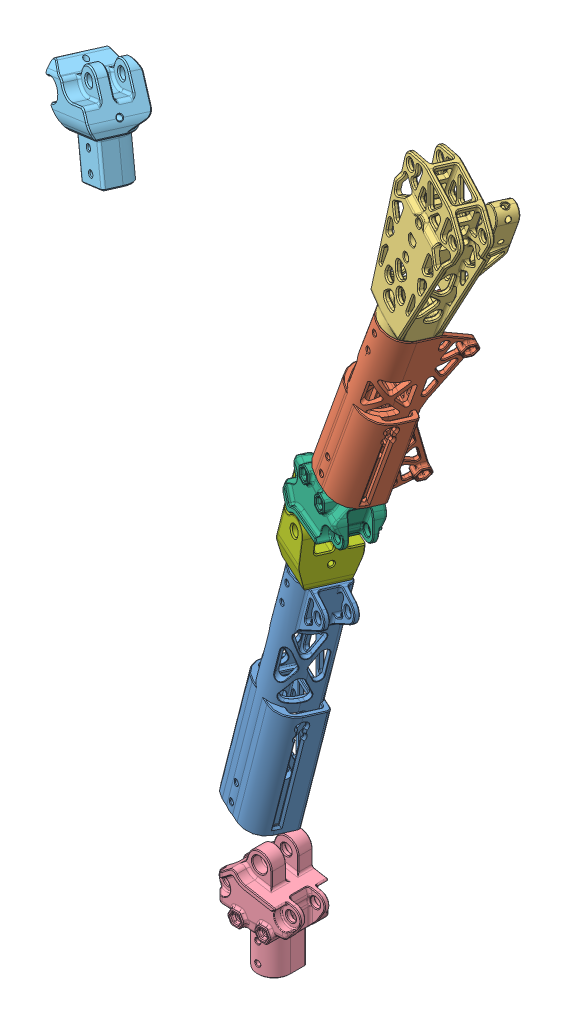
SolidWorks assembly right back leg, configuration Default. Lengths in mm.
Overall size (423.59 516.7 169.39).
7 component instances, 7 part files, 8 mates.
Components (placement in the parent):
- AARL_QR_FR_LE_PL_BL_005.1-4: AARL_QR_FR_LE_PL_BL_005.1 [Default] at (23.665 -332.8832 -154.7317) x (0.294917 -0.089041 -0.951365) z (0.92617 -0.21825 0.307533) size (30.96 157.16 50.8)
- AARL_QR_FR_LE_PL_BL_002.2-4: AARL_QR_FR_LE_PL_BL_002.2 [Default] at (80.0385 -117.9521 -157.1454) x (0.294917 -0.089041 -0.951365) z (0.889564 -0.33792 0.307386) size (49.56 119.06 40.01)
- AARL_QR_FR_LE_PL_BL_012.1-4: AARL_QR_FR_LE_PL_BL_012.1 [Default] at (134.9486 29.5253 -153.9264) x (0.294917 -0.089041 -0.951365) z (0.889564 -0.33792 0.307386) size (53.59 127.48 60.54)
- AARL_QR_FR_LE_PL_BR_003.10-1: AARL_QR_FR_LE_PL_BR_003.10 [Default] at (37.6833 -379.4702 -152.6958) size (54.18 69.85 35.13)
- AARL_QR_FR_LE_PL_BR_004.10-1: AARL_QR_FR_LE_PL_BR_004.10 [Default] at (-195.521 -86.8126 -273.4087) x (0.294917 -0.089041 -0.951365) z (0.906991 0.339364 0.249399) size (36.16 59.22 41.37)
- AARL_QR_FR_LE_PL_BR_006.10-1: AARL_QR_FR_LE_PL_BR_006.10 [Default] at (61.1801 -123.8408 -109.0433) x (0.889564 -0.33792 0.307386) z (0.294917 -0.089041 -0.951365) size (54.18 69.85 35.13)
- AARL_QR_FR_LE_PL_BR_007.10-1: AARL_QR_FR_LE_PL_BR_007.10 [Default] at (67.3646 -152.1819 -158.0975) x (0.294917 -0.089041 -0.951365) z (0.92617 -0.21825 0.307533) size (34.93 68.68 39.69)
Mates (geometry in assembly coordinates):
- Concentric23: concentric aligned: cylinder of AARL_QR_FR_LE_PL_BL_002.2-4 through (121.574 -6.3961 -154.7104) axis (-0.348855 -0.936954 -0.020451) radius 11.1125; cylinder of AARL_QR_FR_LE_PL_BL_012.1-4 through (126.9311 7.992 -154.3964) axis (-0.348855 -0.936954 -0.020451) radius 10.8585
- Concentric24: concentric aligned: cylinder of AARL_QR_FR_LE_PL_BL_002.2-4 through (115.1452 -11.0736 -141.2477) axis (0.294917 -0.089041 -0.951365) radius 1.5875; cylinder of AARL_QR_FR_LE_PL_BL_012.1-4 through (115.6134 -11.2149 -142.758) axis (0.294917 -0.089041 -0.951365) radius 1.5875
- Concentric25: concentric anti-aligned: cylinder of AARL_QR_FR_LE_PL_BL_002.2-4 through (80.0385 -117.9521 -157.1454) axis (0.348855 0.936954 0.020451) radius 11.1125; cylinder of AARL_QR_FR_LE_PL_BR_006.10-1 through (88.8994 -94.1535 -156.6259) axis (-0.348855 -0.936954 -0.020451) radius 10.8585
- Concentric27: concentric aligned: cylinder of AARL_QR_FR_LE_PL_BL_002.2-4 through (82.4705 -98.831 -143.1631) axis (0.294917 -0.089041 -0.951365) radius 1.5875; cylinder of AARL_QR_FR_LE_PL_BR_006.10-1 through (81.5042 -98.5393 -140.0459) axis (0.294917 -0.089041 -0.951365) radius 1.5875
- Concentric30: concentric anti-aligned: cylinder of AARL_QR_FR_LE_PL_BR_006.10-1 through (60.4662 -150.0991 -135.8442) axis (0.294917 -0.089041 -0.951365) radius 4.826; cylinder of AARL_QR_FR_LE_PL_BR_007.10-1 through (72.5146 -153.7368 -174.7107) axis (-0.294917 0.089041 0.951365) radius 3.2385
- Coincident2: coincident anti-aligned: plane of AARL_QR_FR_LE_PL_BR_006.10-1 through (64.4918 -151.3145 -148.8303) normal (-0.294917 0.089041 0.951365); plane of AARL_QR_FR_LE_PL_BR_007.10-1 through (54.5949 -140.8289 -152.8797) normal (0.294917 -0.089041 -0.951365)
- Concentric31: concentric anti-aligned: cylinder of AARL_QR_FR_LE_PL_BL_005.1-4 through (60.6012 -180.1492 -157.5766) axis (-0.235019 -0.971822 0.018101) radius 11.1125; cylinder of AARL_QR_FR_LE_PL_BR_007.10-1 through (54.6317 -204.8335 -157.1168) axis (0.235019 0.971822 -0.018101) radius 9.271
- Concentric32: concentric aligned: cylinder of AARL_QR_FR_LE_PL_BL_005.1-4 through (54.8952 -185.0481 -143.869) axis (0.294917 -0.089041 -0.951365) radius 1.5875; cylinder of AARL_QR_FR_LE_PL_BR_007.10-1 through (61.843 -187.1457 -166.2817) axis (0.294917 -0.089041 -0.951365) radius 1.5875
